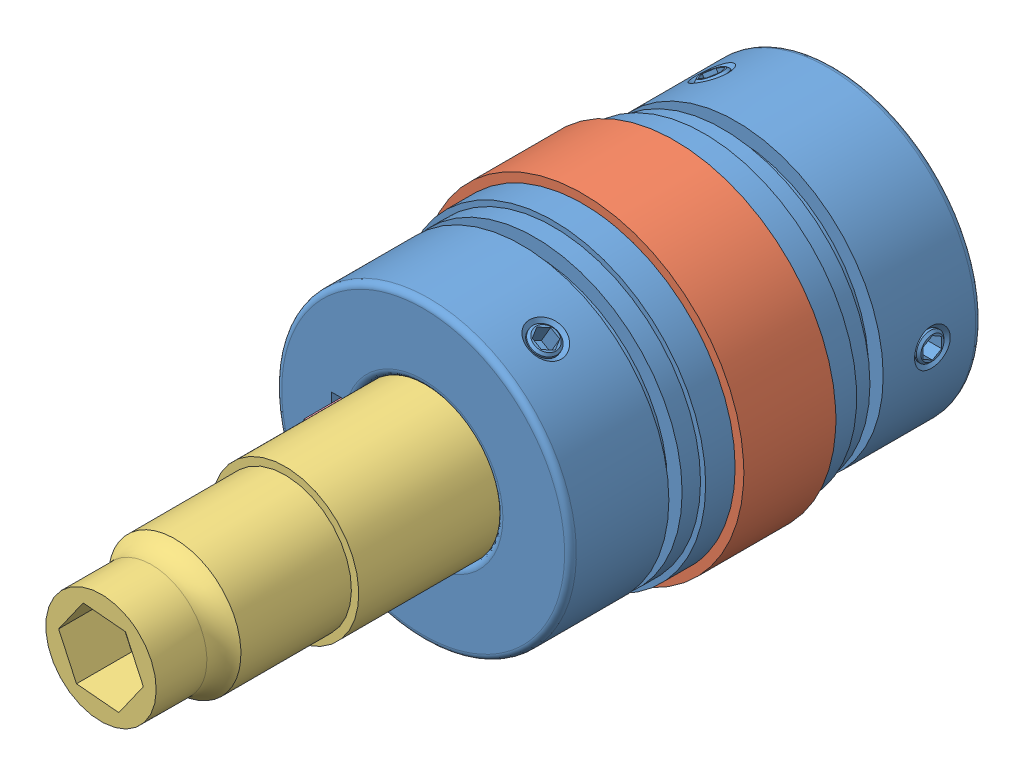
SolidWorks assembly couplerassembly, configuration Default. Lengths in mm.
Overall size (55.56 55.56 126.52).
5 component instances, 4 part files, 10 mates.
Components (placement in the parent):
- CouplerPiece-1: CouplerPiece [3565N164] at (36.8846 41.6241 29.2971) x (0 0 -1) z (1 0 0) size (34.96 52.58 52.58)
- CouplerPiece-2: CouplerPiece [3565N164] at (36.8846 41.6241 55.3321) x (0 0 1) z (-1 0 0) size (34.96 52.58 52.58)
- CouplerConnection-1: CouplerConnection [Default] at (36.8846 41.6241 34.3771) size (55.56 55.56 15.88)
- CouplerShaft-1: CouplerShaft [Default] at (36.8846 41.6241 50.7601) x (0.5719 0.820324 0) z (0 0 1) size (25.4 25.4 82.55)
- 98870A405_STEEL MACHINE KEY-1: 98870A405_STEEL MACHINE KEY [98870A405] at (24.2596 43.9741 66.6351) x (0 0 1) z (-1 0 0) size (31.75 6.35 6.35)
Mates (geometry in assembly coordinates):
- Concentric1: concentric anti-aligned: cylinder of 3565N164_HIGH-TORQUE SET SCREW FLEXIBLE SHAFT COUPLING-1 through (36.8846 41.6241 34.6311) axis (0 0 -1) radius 26.289; cylinder of 3565N164_HIGH-TORQUE SET SCREW FLEXIBLE SHAFT COUPLING-2 through (36.8846 41.6241 49.9981) axis (0 0 1) radius 26.289
- Coincident1: coincident aligned: plane of 3565N164_HIGH-TORQUE SET SCREW FLEXIBLE SHAFT COUPLING-1 through (41.7106 55.0719 34.3771) normal (1 0 0); plane of 3565N164_HIGH-TORQUE SET SCREW FLEXIBLE SHAFT COUPLING-2 through (41.7106 67.4664 50.2521) normal (1 0 0)
- Coincident2: coincident anti-aligned: plane of 3565N164_HIGH-TORQUE SET SCREW FLEXIBLE SHAFT COUPLING-1 through (36.8846 41.6241 34.3771) normal (0 0 1); plane of CouplerConnection-1 through (36.8846 41.6241 34.3771) normal (0 0 -1)
- Coincident3: coincident anti-aligned: plane of 3565N164_HIGH-TORQUE SET SCREW FLEXIBLE SHAFT COUPLING-2 through (36.8846 41.6241 50.2521) normal (0 0 -1); plane of CouplerConnection-1 through (36.8846 41.6241 50.2521) normal (0 0 1)
- Concentric4: concentric aligned: cylinder of 3565N164_HIGH-TORQUE SET SCREW FLEXIBLE SHAFT COUPLING-1 through (36.8846 41.6241 30.4185) axis (0 0 -1) radius 25.4; cylinder of CouplerConnection-1 through (36.8846 41.6241 50.2521) axis (0 0 -1) radius 27.7812
- Concentric5: concentric anti-aligned: cylinder of CouplerPiece-2 through (36.8846 41.6241 12.9991) axis (0 0 1) radius 12.5; cylinder of CouplerShaft-1 through (36.8846 41.6241 101.5601) axis (0 0 -1) radius 12.7
- Coincident5: coincident anti-aligned: circle of CouplerPiece-2; plane of CouplerShaft-1 through (36.8846 41.6241 50.7601) normal (0 0 -1)
- Coincident6: coincident anti-aligned: plane of CouplerPiece-2 through (21.0846 45.6241 12.9991) normal (1 0 0); plane of 98870A405_STEEL MACHINE KEY-1 through (23.7697 38.1272 49.0179) normal (-1 0 0)
- Coincident7: coincident anti-aligned: plane of CouplerPiece-2 through (21.0846 37.6241 12.9991) normal (0 1 0); plane of 98870A405_STEEL MACHINE KEY-1 through (23.7697 38.1272 49.0179) normal (0 -1 0)
- Coincident9: coincident aligned: plane of CouplerShaft-1 through (36.8846 41.6241 50.7601) normal (0 0 -1); plane of 98870A405_STEEL MACHINE KEY-1 through (27.4346 37.6241 50.7601) normal (0 0 -1)
